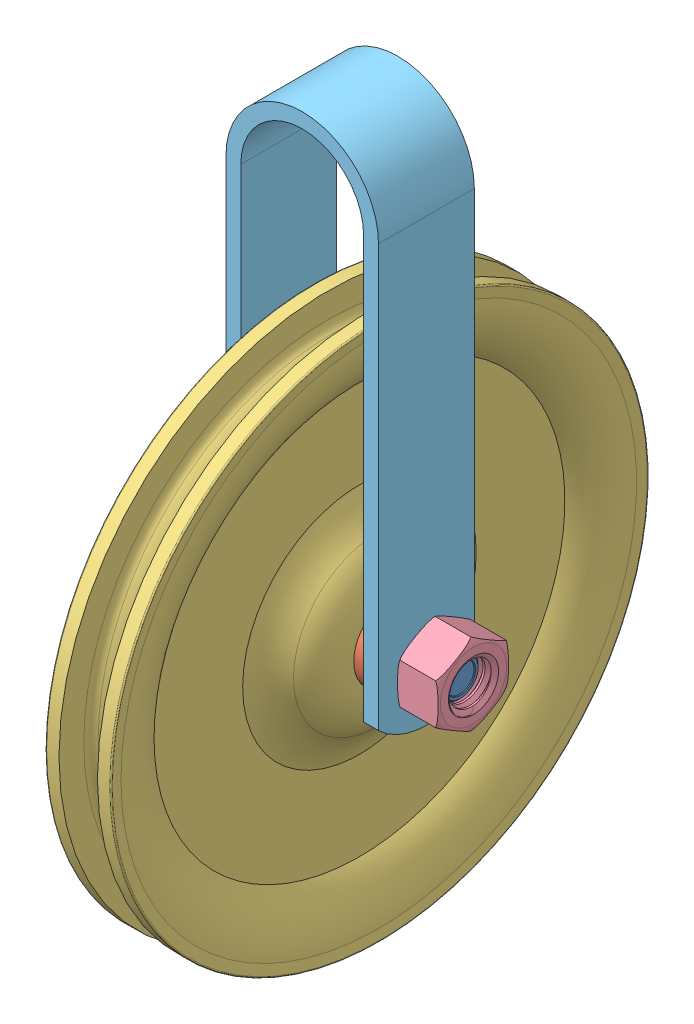
SolidWorks assembly Assembly, configuration Default. Lengths in mm.
Overall size (48.89 146.09 107.92).
5 component instances, 5 part files, 5 mates.
Components (placement in the parent):
- boltRe-1: boltRe [Default] at (-2.6097 27.6467 31.647) x (0 1 0) z (0 0 1) size (16.29 45.02 14.11)
- Cylinder-1: Cylinder [Default] at (19.0087 27.6467 31.647) x (0 1 0) z (0 0 1) size (15.49 23.51 15.49)
- WheelRedraw-2: WheelRedraw [Default] at (18.4687 27.6467 31.647) x (0 1 0) z (0 0 1) size (107.92 18.43 107.92)
- NutRe-1: NutRe [Default] at (39.7185 27.6467 31.647) x (0 1 0) z (0 0 1) size (16.32 10.68 14.14)
- Bracket-1: Bracket [Default] at (3.7704 16.0071 31.647) size (30.61 103.77 19.23)
Mates (geometry in assembly coordinates):
- Concentric7: concentric anti-aligned: cylinder of Cylinder-1 through (17.2549 27.6467 31.647) axis (1 0 0) radius 7.747; cylinder of WheelRedraw-2 through (-0.1066 27.6467 31.647) axis (-1 0 0) radius 7.8803
- ProfileCenter4: profile center = 2 mm: circle of WheelRedraw-2; circle of Cylinder-1
- ProfileCenter5: profile center = 0.5 mm: circle of Cylinder-1; circle of Bracket-1
- ProfileCenter6: profile center = 0.5 mm: circle of boltRe-1; circle of Bracket-1
- Concentric14: concentric aligned: circle of NutRe-1; circle of Bracket-1
